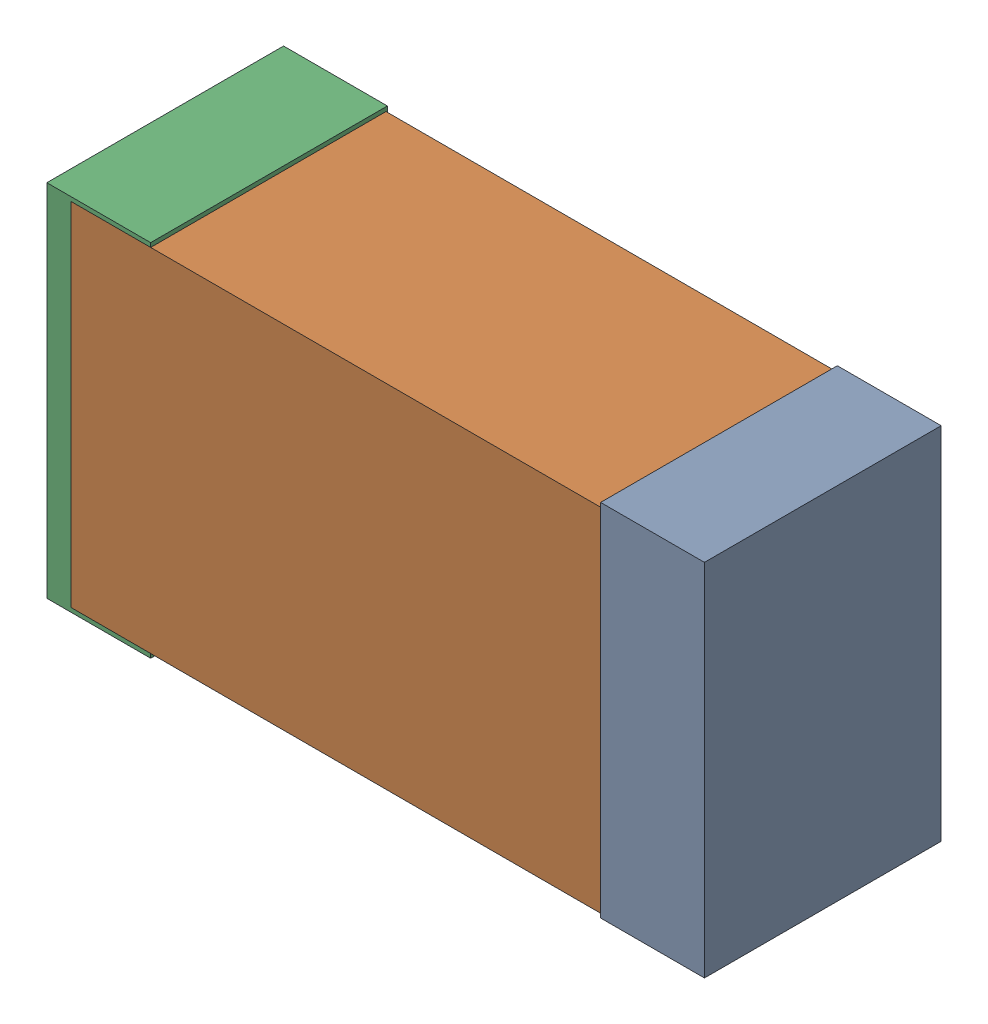
SolidWorks assembly USB01_C8, configuration Default. Lengths in mm.
Overall size (2.38 1.3 0.85).
6 component instances, 2 part files, 0 mates.
Components (placement in the parent):
- 384311232-1: 384311232 [Default] at (157.718 77.597 -1.9574) size (0.38 1.3 0.85)
  - Extruded_8-1: Extruded_8 [Default] at origin size (0.38 1.3 0.85)
- 384311360-1: 384311360 [Default] at (156.718 77.597 -1.9524) size (2.2 1.27 0.85)
  - Extruded_9-1: Extruded_9 [Default] at origin size (2.2 1.27 0.85)
- 384311232-2: 384311232 [Default] at (155.718 77.597 -1.9574) size (0.38 1.3 0.85)
  - Extruded_8-1: Extruded_8 [Default] at origin size (0.38 1.3 0.85)
